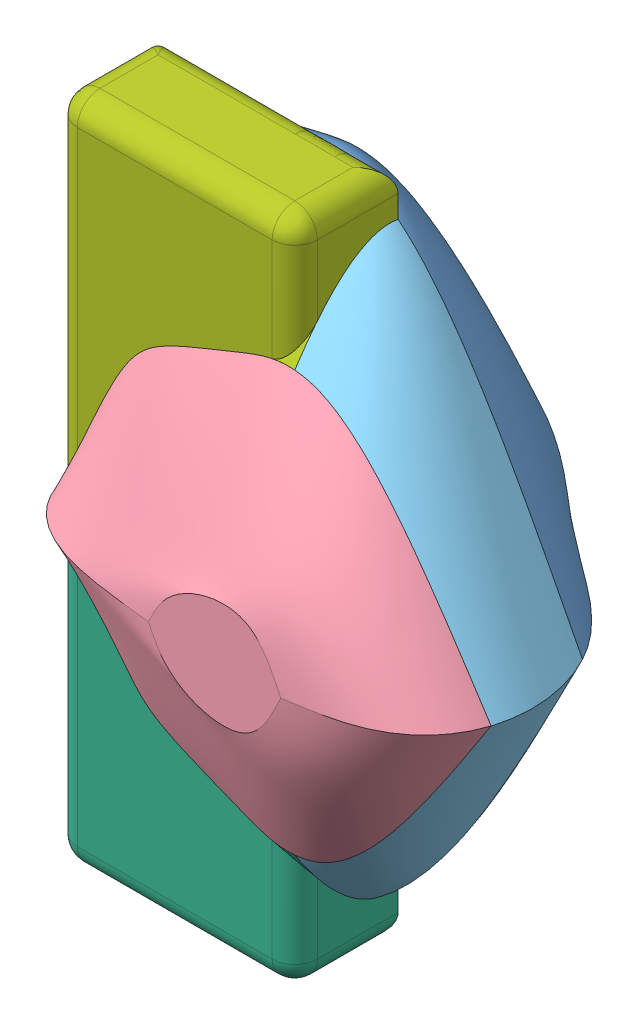
SolidWorks assembly head assm, configuration Default. Lengths in mm.
8 component instances, 8 part files, 24 mates.
Components (placement in the parent):
- bottom back left-1: bottom back left [Default] at (-8.7658 0 43.6041) x (0 -1 0) z (0 0 -1) size (157.97 187.29 45.46)
- bottom back right-1: bottom back right [Default] at (-8.7658 0 43.6041) x (0 -1 0) z (0 0 -1) size (148.08 181.11 51.5)
- bottom front-1: bottom front [Default] at (-68.4234 0 -9.4455) x (0 -1 0) z (-0.936784 0 0.34991) size (164.21 114.96 29.45)
- crown v4-1: crown v4 [Default] at (-8.7658 0 40) x (0 -1 0) z (-1 0 0) size (208.19 39.02 188.74)
- middle back-1: middle back [Default] at (-8.7658 0 40) x (0 -1 0) z (-1 0 0) size (272.97 45.63 106.33)
- visor middle front right-1: visor middle front right [Default] at (-8.2725 -147.5 67.2082) x (1 0 0) z (0 1 0) size (109.8 45.62 147.52)
- visor middle front left-1: visor middle front left [Default] at (-8.2725 147.5 67.2082) x (-1 0 0) z (0 -1 0) size (109.8 45.62 147.52)
- mouth plate-1: mouth plate [Default] at (-86.0575 -0.1211 -25.0069) x (0 -1 0) z (-0.989195 0 0.146609) size (50.2 57.5 7)
Mates (geometry in assembly coordinates):
- Coincident1: coincident: point of ?; point of ?
- Coincident2: coincident: point of ?; point of ?
- Coincident3: coincident anti-aligned: plane of ? through (-8.7658 0 43.6041) normal (0 -1 0); plane of ? through (-8.7658 0 43.6041) normal (0 1 0)
- Coincident4: coincident: point of ?; point of ?
- Coincident5: coincident anti-aligned: plane of ? through (-8.7658 0 43.6041) normal (0 0 1); plane of ? through (27.2342 147.5 43.6041) normal (0 0 -1)
- Coincident6: coincident: curve of ?
- Coincident9: coincident anti-aligned: plane of ? through (-64.7658 0 43.6041) normal (-1 0 0); plane of bottom front-1 through (-64.7658 0 43.6041) normal (1 0 0)
- Coincident10: coincident: point of ?; moEndPointRef_w of bottom front-1
- Coincident11: coincident aligned: plane of ? through (-8.7658 0 43.6041) normal (0 0 1); plane of bottom front-1 through (-8.7658 0 43.6041) normal (0 0 1)
- Coincident12: coincident: point of ?; point of ?
- Coincident14: coincident: point of visor middle front right-1; point of visor middle front left-1
- Coincident15: coincident: point of visor middle front right-1; point of visor middle front left-1
- Coincident16: coincident anti-aligned: plane of visor middle front right-1 through (-8.7658 0 40) normal (0 1 0); plane of visor middle front left-1 through (-8.7658 0 40) normal (0 -1 0)
- Coincident17: coincident anti-aligned: plane of visor middle front left-1 through (27.2342 147.5 43.6041) normal (0 0 -1); plane of ? through (-8.7658 0 43.6041) normal (0 0 1)
- Coincident18: coincident: moEndPointRef_w of bottom front-1; point of visor middle front right-1
- Parallel1: parallel aligned: plane of ? through (-53.7658 0 43.6041) normal (1 0 0); plane of visor middle front right-1 through (-76.2658 147.5 43.6041) normal (1 0 0)
- Coincident20: coincident: point of ?; point of visor middle front right-1
- Coincident21: coincident anti-aligned: plane of ? through (-8.7658 0 89.2269) normal (0 0 -1); plane of visor middle front right-1 through (27.2342 147.5 89.2269) normal (0 0 1)
- Coincident22: coincident anti-aligned: plane of mouth plate-1 through (-90.2725 24.9789 -53.4462) normal (0.989195 0 -0.146609); plane of bottom front-1 through (-81.8055 16.5919 3.6819) normal (-0.989195 0 0.146609)
- Coincident23: coincident: point of bottom front-1; point of mouth plate-1
- Parallel2: parallel anti-aligned: plane of mouth plate-1 through (-85.7992 16.3789 4.0189) normal (0.146609 0 0.989195); plane of bottom front-1 through (-81.8055 -16.5919 3.6819) normal (-0.146609 0 -0.989195)
- Concentric1: concentric: cylinder of ?
- Coincident29: coincident anti-aligned: unknown of ?
- Coincident30: coincident: line of ?
